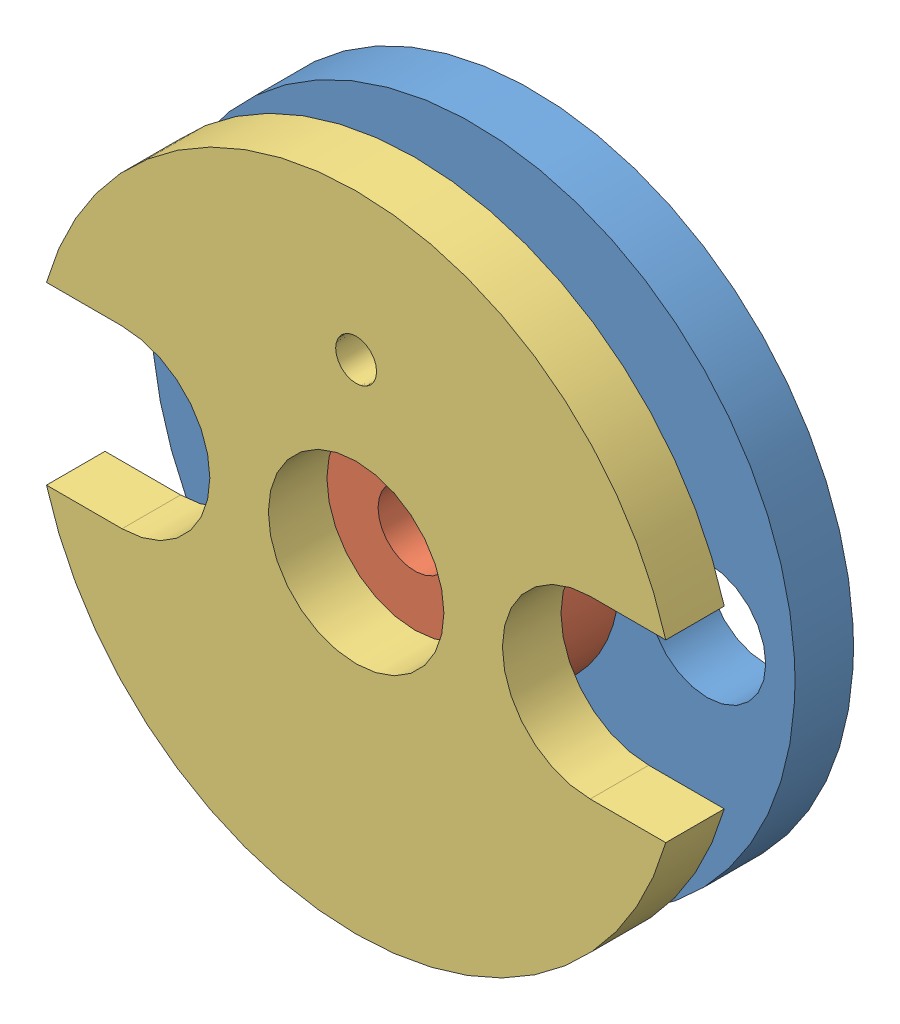
SolidWorks assembly servoPulley, configuration Default. Lengths in mm.
Overall size (22 22 6).
3 component instances, 3 part files, 6 mates.
Components (placement in the parent):
- servoPulleyAX12_1-1: servoPulleyAX12_1 [Default] at (-2466.0963 -997.3365 18.1212) size (22 22 2)
- servoPulleyAX12_2-1: servoPulleyAX12_2 [Default] at (-2466.0963 -997.3365 20.1212) size (10 10 2)
- servoPulleyAX12_3-1: servoPulleyAX12_3 [Default] at (-2466.0963 -997.3365 22.1212) size (21.17 22 2)
Mates (geometry in assembly coordinates):
- Concentric1: concentric aligned: circle of servoPulleyAX12_1-1; circle of servoPulleyAX12_2-1
- Concentric2: concentric aligned: circle of servoPulleyAX12_2-1; circle of servoPulleyAX12_3-1
- Concentric3: concentric aligned: circle of servoPulleyAX12_1-1; circle of servoPulleyAX12_3-1
- Concentric4: concentric anti-aligned: circle of servoPulleyAX12_1-1; circle of servoPulleyAX12_3-1
- Coincident2: coincident anti-aligned: plane of servoPulleyAX12_1-1 through (-2466.0963 -997.3365 20.1212) normal (0 0 1); plane of servoPulleyAX12_2-1 through (-2466.0963 -997.3365 20.1212) normal (0 0 -1)
- Coincident3: coincident anti-aligned: circle of servoPulleyAX12_2-1; plane of servoPulleyAX12_3-1 through (-2466.0963 -997.3365 22.1212) normal (0 0 -1)
